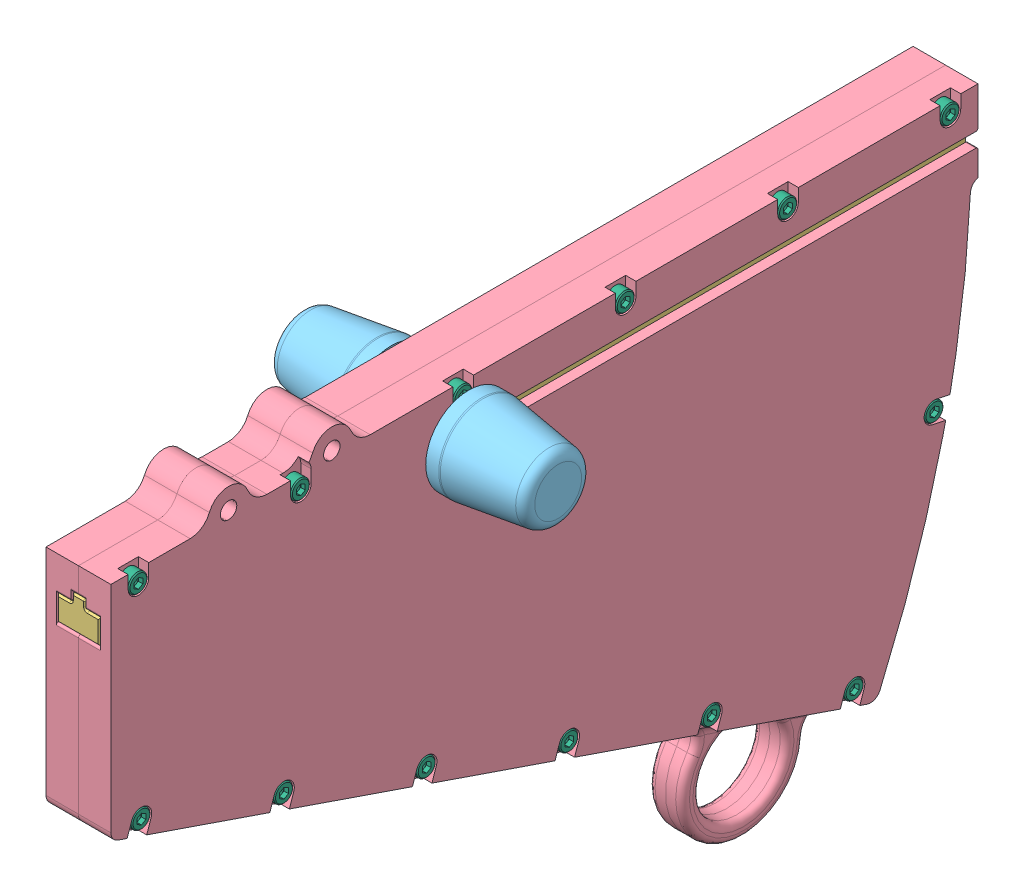
SolidWorks assembly Zip Tie Installer Magazine, configuration Default. Lengths in mm.
Overall size (74.46 167.94 252).
35 component instances, 10 part files, 0 mates.
Components (placement in the parent):
- Zip Tie Gate^Zip Tie Installer-1: Zip Tie Gate^Zip Tie Installer [Default] at origin size (15.26 15.54 11.97)
- Follower^Zip Tie Installer-1: Follower^Zip Tie Installer [Default] at origin size (15.26 90.11 217.12)
- Pusher^Zip Tie Installer-1: Pusher^Zip Tie Installer [Default] at (0 0 -8) size (12.46 9.7 252)
- Magazine Casing^Zip Tie Installer-1: Magazine Casing^Zip Tie Installer [Default] at origin size (18.86 167.94 252)
- Knob-1: Knob [Default] at (-11.23 -35.384 -148) x (0 0 1) z (-1 0 0) size (25 25 26)
- Knob-2: Knob [Default] at (11.23 -35.384 -148) x (0 0 -1) z (1 0 0) size (25 25 26)
- socket head cap screw_am(B18.3.1M - 3 x 0.5 x 10 Hex SHCS -- 10NHX)-1: socket head cap screw_am(B18.3.1M - 3 x 0.5 x 10 Hex SHCS -- 10NHX) [Default] at (9.43 -127.7086 -179.0177) x (-1 0 0) z (0 0 -1) size (13 5.5 5.5)
- socket head cap screw_am(B18.3.1M - 3 x 0.5 x 10 Hex SHCS -- 10NHX)-2: socket head cap screw_am(B18.3.1M - 3 x 0.5 x 10 Hex SHCS -- 10NHX) [Default] at (9.43 -25.334 -101) x (-1 0 0) z (0 0 -1) size (13 5.5 5.5)
- socket head cap screw_am(B18.3.1M - 3 x 0.5 x 10 Hex SHCS -- 10NHX)-3: socket head cap screw_am(B18.3.1M - 3 x 0.5 x 10 Hex SHCS -- 10NHX) [Default] at (9.43 -25.334 -148.2) x (-1 0 0) z (0 0 -1) size (13 5.5 5.5)
- socket head cap screw_am(B18.3.1M - 3 x 0.5 x 10 Hex SHCS -- 10NHX)-4: socket head cap screw_am(B18.3.1M - 3 x 0.5 x 10 Hex SHCS -- 10NHX) [Default] at (9.43 -25.334 -195.4) x (-1 0 0) z (0 0 -1) size (13 5.5 5.5)
- socket head cap screw_am(B18.3.1M - 3 x 0.5 x 10 Hex SHCS -- 10NHX)-5: socket head cap screw_am(B18.3.1M - 3 x 0.5 x 10 Hex SHCS -- 10NHX) [Default] at (9.43 -85.0732 -54.6649) x (-1 0 0) z (0 0 -1) size (13 5.5 5.5)
- socket head cap screw_am(B18.3.1M - 3 x 0.5 x 10 Hex SHCS -- 10NHX)-6: socket head cap screw_am(B18.3.1M - 3 x 0.5 x 10 Hex SHCS -- 10NHX) [Default] at (9.43 -141.9204 -220.4686) x (-1 0 0) z (0 0 -1) size (13 5.5 5.5)
- socket head cap screw_am(B18.3.1M - 3 x 0.5 x 10 Hex SHCS -- 10NHX)-7: socket head cap screw_am(B18.3.1M - 3 x 0.5 x 10 Hex SHCS -- 10NHX) [Default] at (9.43 -97.8394 -285.129) x (-1 0 0) z (0 0 -1) size (13 5.5 5.5)
- socket head cap screw_am(B18.3.1M - 3 x 0.5 x 10 Hex SHCS -- 10NHX)-8: socket head cap screw_am(B18.3.1M - 3 x 0.5 x 10 Hex SHCS -- 10NHX) [Default] at (9.43 -113.4968 -137.5667) x (-1 0 0) z (0 0 -1) size (13 5.5 5.5)
- socket head cap screw_am(B18.3.1M - 3 x 0.5 x 10 Hex SHCS -- 10NHX)-9: socket head cap screw_am(B18.3.1M - 3 x 0.5 x 10 Hex SHCS -- 10NHX) [Default] at (9.43 -25.334 -242.6) x (-1 0 0) z (0 0 -1) size (13 5.5 5.5)
- socket head cap screw_am(B18.3.1M - 3 x 0.5 x 10 Hex SHCS -- 10NHX)-10: socket head cap screw_am(B18.3.1M - 3 x 0.5 x 10 Hex SHCS -- 10NHX) [Default] at (9.43 -156.1322 -261.9195) x (-1 0 0) z (0 0 -1) size (13 5.5 5.5)
- socket head cap screw_am(B18.3.1M - 3 x 0.5 x 10 Hex SHCS -- 10NHX)-11: socket head cap screw_am(B18.3.1M - 3 x 0.5 x 10 Hex SHCS -- 10NHX) [Default] at (9.43 -25.334 -289.8) x (-1 0 0) z (0 0 -1) size (13 5.5 5.5)
- socket head cap screw_am(B18.3.1M - 3 x 0.5 x 10 Hex SHCS -- 10NHX)-12: socket head cap screw_am(B18.3.1M - 3 x 0.5 x 10 Hex SHCS -- 10NHX) [Default] at (9.43 -25.334 -53.8) x (-1 0 0) z (0 0 -1) size (13 5.5 5.5)
- socket head cap screw_am(B18.3.1M - 3 x 0.5 x 10 Hex SHCS -- 10NHX)-13: socket head cap screw_am(B18.3.1M - 3 x 0.5 x 10 Hex SHCS -- 10NHX) [Default] at (9.43 -99.285 -96.1158) x (-1 0 0) z (0 0 -1) size (13 5.5 5.5)
- Dowel Pin 4mm(50mm)-1: Dowel Pin 4mm(50mm) [Default] at (0 -35.384 -148) x (0 0 1) z (-1 0 0) size (4 4 50)
- Compression Spring 10mm-1: Compression Spring 10mm [Default] at (0 -57.02 -54.984) size (6.82 12.35 6.82)
- Rectangular Spring-1: Rectangular Spring [Default] at (0 -102.0188 -164.5225) x (0 -0.324325 -0.945946) z (-1 0 0) size (180.85 16.04 8.85)
- 94180A331_HEAT-SET INSERTS FOR PLASTICS-1: 94180A331_HEAT-SET INSERTS FOR PLASTICS [Default] at (0 -25.334 -53.8) x (0 -1 0) z (0 0 1) size (5.56 4.12 5.56)
- 94180A331_HEAT-SET INSERTS FOR PLASTICS-2: 94180A331_HEAT-SET INSERTS FOR PLASTICS [Default] at (0 -25.334 -195.4) x (0 -1 0) z (0 0 1) size (5.56 4.12 5.56)
- 94180A331_HEAT-SET INSERTS FOR PLASTICS-3: 94180A331_HEAT-SET INSERTS FOR PLASTICS [Default] at (0 -97.8394 -285.129) x (0 -1 0) z (0 0 1) size (5.56 4.12 5.56)
- 94180A331_HEAT-SET INSERTS FOR PLASTICS-4: 94180A331_HEAT-SET INSERTS FOR PLASTICS [Default] at (0 -141.9204 -220.4686) x (0 -1 0) z (0 0 1) size (5.56 4.12 5.56)
- 94180A331_HEAT-SET INSERTS FOR PLASTICS-5: 94180A331_HEAT-SET INSERTS FOR PLASTICS [Default] at (0 -127.7086 -179.0177) x (0 -1 0) z (0 0 1) size (5.56 4.12 5.56)
- 94180A331_HEAT-SET INSERTS FOR PLASTICS-6: 94180A331_HEAT-SET INSERTS FOR PLASTICS [Default] at (0 -113.4968 -137.5667) x (0 -1 0) z (0 0 1) size (5.56 4.12 5.56)
- 94180A331_HEAT-SET INSERTS FOR PLASTICS-7: 94180A331_HEAT-SET INSERTS FOR PLASTICS [Default] at (0 -156.1322 -261.9195) x (0 -1 0) z (0 0 1) size (5.56 4.12 5.56)
- 94180A331_HEAT-SET INSERTS FOR PLASTICS-8: 94180A331_HEAT-SET INSERTS FOR PLASTICS [Default] at (0 -25.334 -242.6) x (0 -1 0) z (0 0 1) size (5.56 4.12 5.56)
- 94180A331_HEAT-SET INSERTS FOR PLASTICS-9: 94180A331_HEAT-SET INSERTS FOR PLASTICS [Default] at (0 -85.0732 -54.6649) x (0 -1 0) z (0 0 1) size (5.56 4.12 5.56)
- 94180A331_HEAT-SET INSERTS FOR PLASTICS-10: 94180A331_HEAT-SET INSERTS FOR PLASTICS [Default] at (0 -99.285 -96.1158) x (0 -1 0) z (0 0 1) size (5.56 4.12 5.56)
- 94180A331_HEAT-SET INSERTS FOR PLASTICS-11: 94180A331_HEAT-SET INSERTS FOR PLASTICS [Default] at (0 -25.334 -148.2) x (0 -1 0) z (0 0 1) size (5.56 4.12 5.56)
- 94180A331_HEAT-SET INSERTS FOR PLASTICS-12: 94180A331_HEAT-SET INSERTS FOR PLASTICS [Default] at (0 -25.334 -101) x (0 -1 0) z (0 0 1) size (5.56 4.12 5.56)
- 94180A331_HEAT-SET INSERTS FOR PLASTICS-13: 94180A331_HEAT-SET INSERTS FOR PLASTICS [Default] at (0 -25.334 -289.8) x (0 -1 0) z (0 0 1) size (5.56 4.12 5.56)
